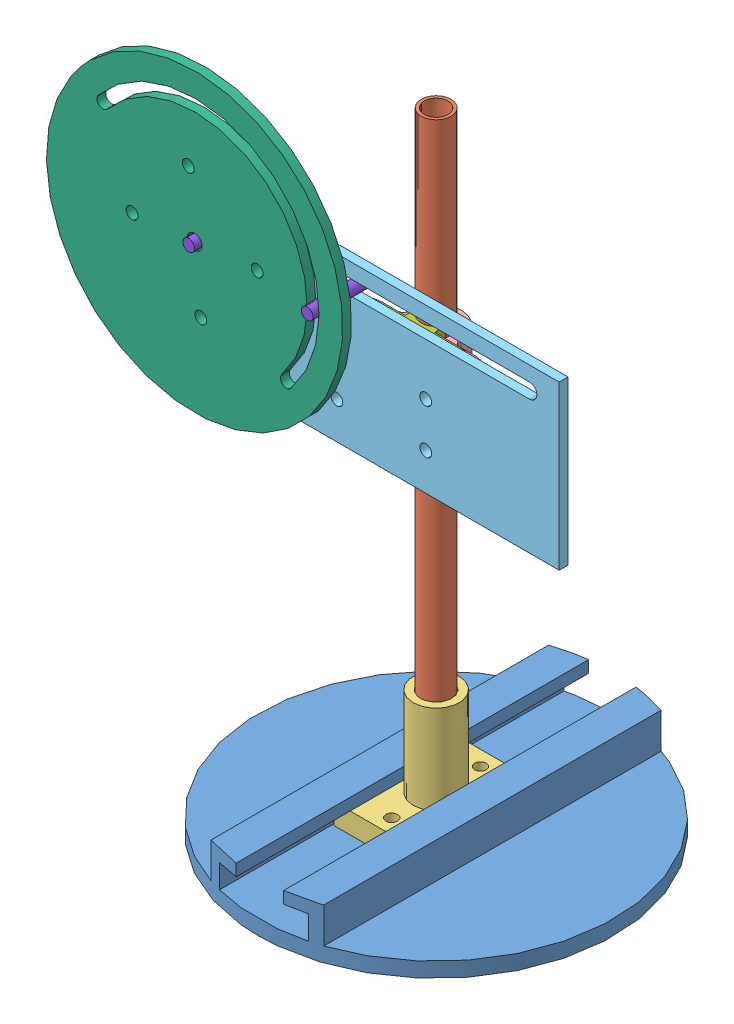
SolidWorks assembly 3eksen, configuration sabit. Lengths in mm.
Overall size (195.36 233.95 150).
10 component instances, 8 part files, 24 mates.
Components (placement in the parent):
- kanallı tabla-1: kanallı tabla [Default] at origin size (150 17 150)
- boru-1: boru [Default] at (0 12 0) x (0.999948 0 0.010184) z (-0.010184 0 0.999948) size (10 200 10)
- kanal yolcusu-1: kanal yolcusu [Default] at (0 8.5 0) size (29 37 40)
- kelepçe-1: kelepçe [Default] at (0 143.5938 0) x (1 0 0) z (0 1 0) size (40 14 10)
- pleksi taşıyıcı-1: pleksi taşıyıcı [Default] at (0 143.5938 17) size (120 55 3)
- rotater-1: rotater [Default] at (-50 163.5938 31.5) x (-0.774039 0.633138 0) z (0 0 -1) size (100 100 3)
- kelepçe-2: kelepçe [Default] at (0 128.5938 0) x (1 0 0) z (0 1 0) size (40 14 10)
- ara parça-1: ara parça [Default] at (0 136.0938 5.5) size (46 31 13.71)
- pim-1: pim [Default] at (-10 163.5938 13.5) x (-0.973823 -0.227308 0) z (-0.227308 0.973823 0) size (4 20 4)
- pim-2: pim [Default] at (-50 163.5938 33.5) x (0.954956 0.296748 0) z (-0.296748 0.954956 0) size (4 20 4)
Mates (geometry in assembly coordinates):
- Concentric1: concentric aligned: cylinder of boru-1 through (0 212 0) axis (0 -1 0) radius 5; cylinder of kanal yolcusu-1 through (0 42 0) axis (0 -1 0) radius 5.25
- Coincident1: coincident anti-aligned: plane of boru-1 through (0 12 0) normal (0 -1 0); plane of kanal yolcusu-1 through (-14.5 12 20) normal (0 1 0)
- Coincident2: coincident anti-aligned: plane of kanallı tabla-1 through (0 5 0) normal (0 1 0); plane of kanal yolcusu-1 through (-14.5 5 20) normal (0 -1 0)
- Width1: width anti-aligned: plane of kanal yolcusu-1 through (14.5 12 20) normal (1 0 0); plane of kanallı tabla-1 through (-14.5 12 20) normal (-1 0 0); plane of kanal yolcusu-1 through (15 0 75.001) normal (-1 0 0); plane of kanallı tabla-1 through (-15 0 75.001) normal (1 0 0)
- Coincident3: coincident anti-aligned: plane of kelepçe-1 through (0 148.5938 5.5) normal (0 0 1); plane of ara parça-1 through (0 136.0938 5.5) normal (0 0 -1)
- Concentric2: concentric aligned: cylinder of kelepçe-1 through (15 143.5938 5.5) axis (0 0 -1) radius 2; cylinder of pleksi taşıyıcı-1 through (15 143.5938 18.5) axis (0 0 -1) radius 2
- Concentric4: concentric aligned: cylinder of kelepçe-1 through (-15 143.5938 5.5) axis (0 0 -1) radius 2; cylinder of pleksi taşıyıcı-1 through (-15 143.5938 18.5) axis (0 0 -1) radius 2
- Concentric5: concentric aligned: cylinder of boru-1 through (0 212 0) axis (0 -1 0) radius 5; cylinder of kelepçe-1 through (0 148.5938 0) axis (0 -1 0) radius 5.5
- Slot1: slot anti-aligned: cylinder of rotater-1 through (-50 163.5938 28.5) axis (0 0 1) radius 2.5; plane of pleksi taşıyıcı-1 through (-50 161.0938 18.5) normal (0 1 0); cylinder of pleksi taşıyıcı-1 through (-50 163.5938 18.5) axis (0 0 -1) radius 2.5
- Distance1: distance = 10 mm anti-aligned: plane of rotater-1 through (-50 163.5938 28.5) normal (0 0 -1); plane of pleksi taşıyıcı-1 through (0 143.5938 18.5) normal (0 0 1)
- Coincident5: coincident anti-aligned: plane of ara parça-1 through (0 136.0938 5.5) normal (0 0 -1); plane of kelepçe-2 through (0 133.5938 5.5) normal (0 0 1)
- Concentric6: concentric aligned: cylinder of pleksi taşıyıcı-1 through (15 128.5938 18.5) axis (0 0 -1) radius 2; cylinder of kelepçe-2 through (15 128.5938 5.5) axis (0 0 -1) radius 2
- Concentric7: concentric aligned: cylinder of pleksi taşıyıcı-1 through (-15 128.5938 18.5) axis (0 0 -1) radius 2; cylinder of kelepçe-2 through (-15 128.5938 5.5) axis (0 0 -1) radius 2
- Coincident7: coincident anti-aligned: plane of pleksi taşıyıcı-1 through (0 143.5938 15.5) normal (0 0 -1); plane of ara parça-1 through (0 136.0938 15.5) normal (0 0 1)
- Concentric8: concentric aligned: cylinder of pleksi taşıyıcı-1 through (-15 143.5938 18.5) axis (0 0 -1) radius 2; cylinder of ara parça-1 through (-15 143.5938 15.5) axis (0 0 -1) radius 2
- Concentric10: concentric aligned: cylinder of pleksi taşıyıcı-1 through (-15 128.5938 18.5) axis (0 0 -1) radius 2; cylinder of ara parça-1 through (-15 128.5938 15.5) axis (0 0 -1) radius 2
- Slot2: slot anti-aligned: cylinder of pim-1 through (-10 163.5938 33.5) axis (0 0 -1) radius 2; cylinder of rotater-1 through (-50 163.5938 28.5) axis (0 0 1) radius 38; cylinder of rotater-1 through (-19.0385 138.2682 28.5) axis (0 0 1) radius 2
- Slot3: slot aligned: cylinder of pim-1 through (-10 163.5938 33.5) axis (0 0 -1) radius 2; plane of pleksi taşıyıcı-1 through (-50 161.0938 18.5) normal (0 1 0); cylinder of pleksi taşıyıcı-1 through (-50 163.5938 18.5) axis (0 0 -1) radius 2.5
- Width2: width aligned: plane of pim-1 through (-10 163.5938 13.5) normal (0 0 -1); plane of pleksi taşıyıcı-1 through (-10 163.5938 33.5) normal (0 0 1); plane of pim-1 through (0 143.5938 15.5) normal (0 0 -1); plane of rotater-1 through (-50 163.5938 31.5) normal (0 0 1)
- Concentric11: concentric aligned: cylinder of kanallı tabla-1 through (0 5 0) axis (0 -1 0) radius 75; cylinder of kanal yolcusu-1 through (0 42 0) axis (0 -1 0) radius 7.75
- Parallel1: parallel aligned: plane of pleksi taşıyıcı-1 through (0 143.5938 18.5) normal (0 0 1)
- Concentric12: concentric aligned: cylinder of rotater-1 through (-50 163.5938 28.5) axis (0 0 1) radius 2.5; cylinder of pim-2 through (-50 163.5938 13.5) axis (0 0 1) radius 2
- Width3: width aligned: plane of pleksi taşıyıcı-1 through (0 143.5938 15.5) normal (0 0 -1); plane of pim-2 through (-50 163.5938 31.5) normal (0 0 1); plane of rotater-1 through (-50 163.5938 13.5) normal (0 0 -1); plane of pim-2 through (-50 163.5938 33.5) normal (0 0 1)
- LimitDistance1: limit distance = 60.4062 mm aligned: plane of ara parça-1 through (-23 151.5938 15.5) normal (0 1 0); plane of boru-1 through (0 212 0) normal (0 1 0)
